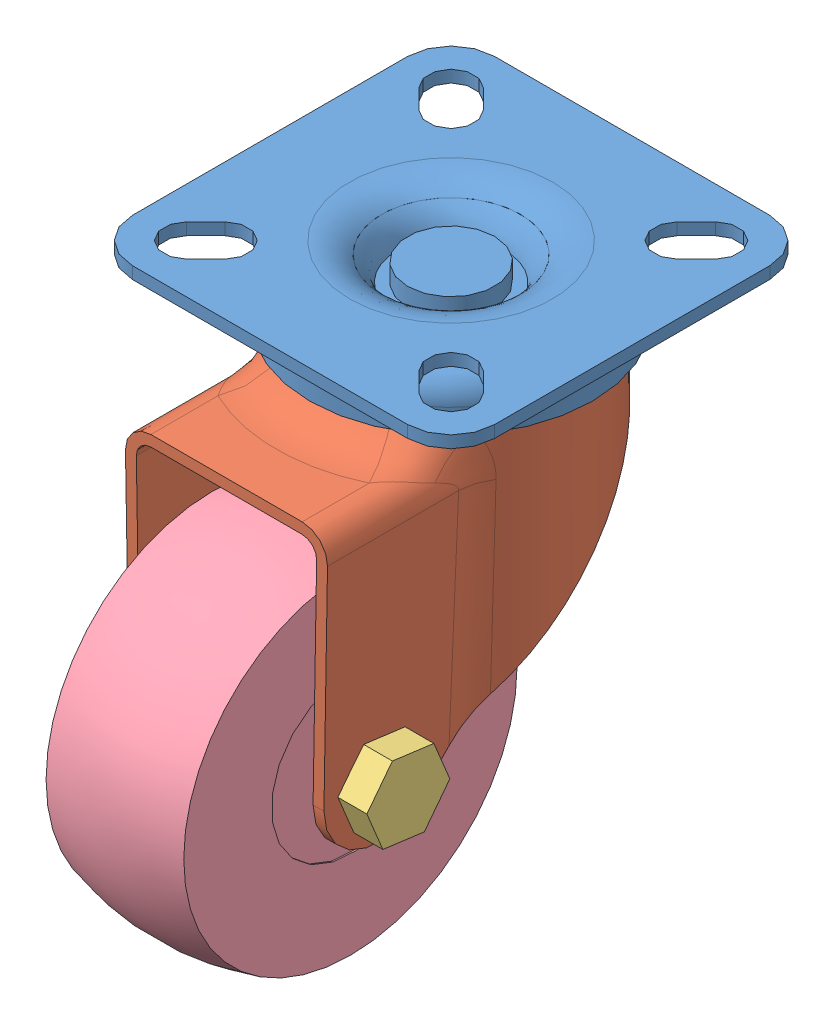
SolidWorks assembly caster v2, configuration caster_51mm. Lengths in mm.
Overall size (50 70.4 72.8).
4 component instances, 4 part files, 7 mates.
Components (placement in the parent):
- casterPlate_v2-1: casterPlate_v2 [Default] at origin size (50 17.66 50)
- casterCarrier_v2-1: casterCarrier_v2 [Default] at origin size (34.9 46.44 48.45)
- casterBolt-1: casterBolt [Default] at (13.5 -44.34 23.4) x (-1 0 0) z (0 0.924225 0.381849) size (39 10 11.55)
- casterWheel_v2-1: casterWheel_v2 [Default] at (0 -44.34 23.4) x (0 1 0) z (0 0 1) size (48.8 23 48.8)
Mates (geometry in assembly coordinates):
- Coincident1: coordinate: point of casterPlate_v2-1
- Coincident2: coincident aligned: plane of casterCarrier_v2-1 through (0 0 0) normal (0 1 0)
- Coincident3: coincident aligned: line of casterPlate_v2-1 through (0 -2.1474 0) axis (0 1 0); line of casterCarrier_v2-1 through (0 -2.1474 0) axis (0 1 0)
- Concentric1: concentric anti-aligned: cylinder of casterCarrier_v2-1 through (-17.45 -44.34 23.4) axis (1 0 0) radius 3; line of casterBolt-1 through (19.45 -44.34 23.4) axis (-1 0 0)
- Coincident4: coincident anti-aligned: plane of casterBolt-1 through (0 -44.34 23.4) normal (-1 0 0)
- Concentric2: concentric anti-aligned: line of casterBolt-1 through (19.45 -44.34 23.4) axis (-1 0 0); cylinder of casterWheel_v2-1 through (0 -44.34 23.4) axis (1 0 0) radius 3
- Coincident5: coincident anti-aligned: plane of casterWheel_v2-1 through (0 -44.34 23.4) normal (-1 0 0)
